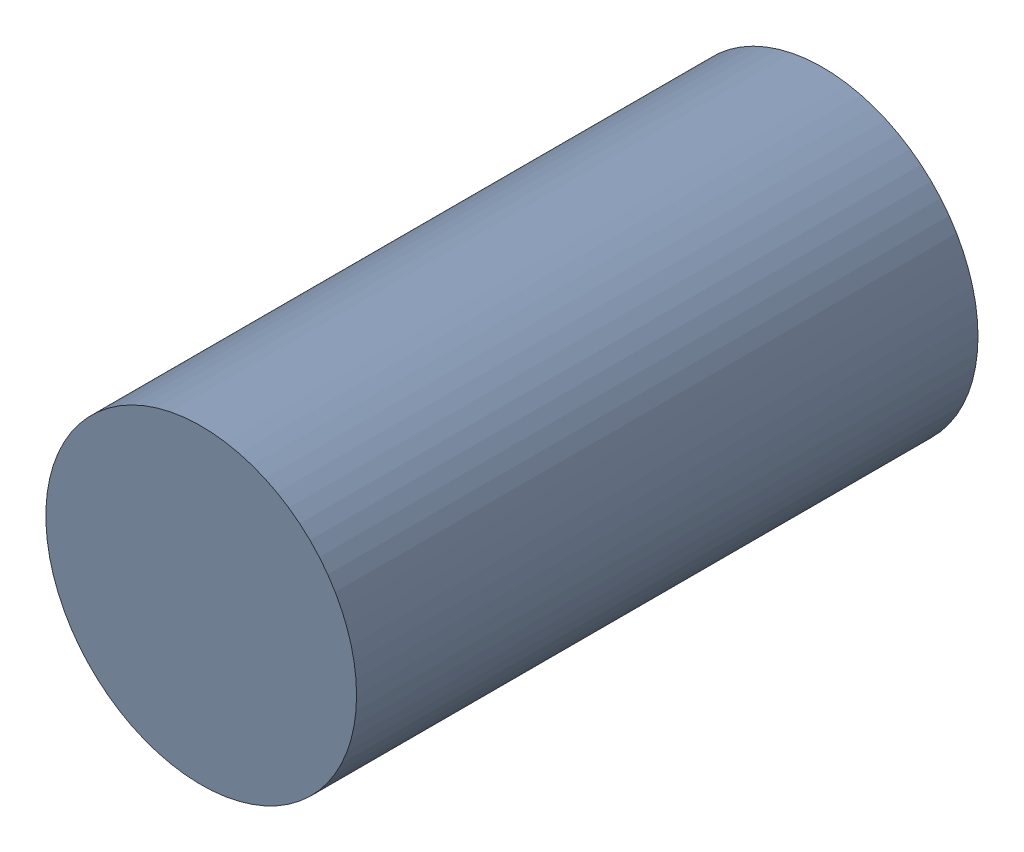
SolidWorks assembly MH10_1.step, configuration Default. Lengths in mm.
Overall size (1 1 2).
2 component instances, 1 part files, 0 mates.
Components (placement in the parent):
- 9228463120_1.step-11: 9228463120_1.step [Default] at (365.9996 301.0003 -1.5) size (1 1 2)
  - Cylinder_1.step-98: Cylinder_1.step [Default] at origin size (1 1 2)
